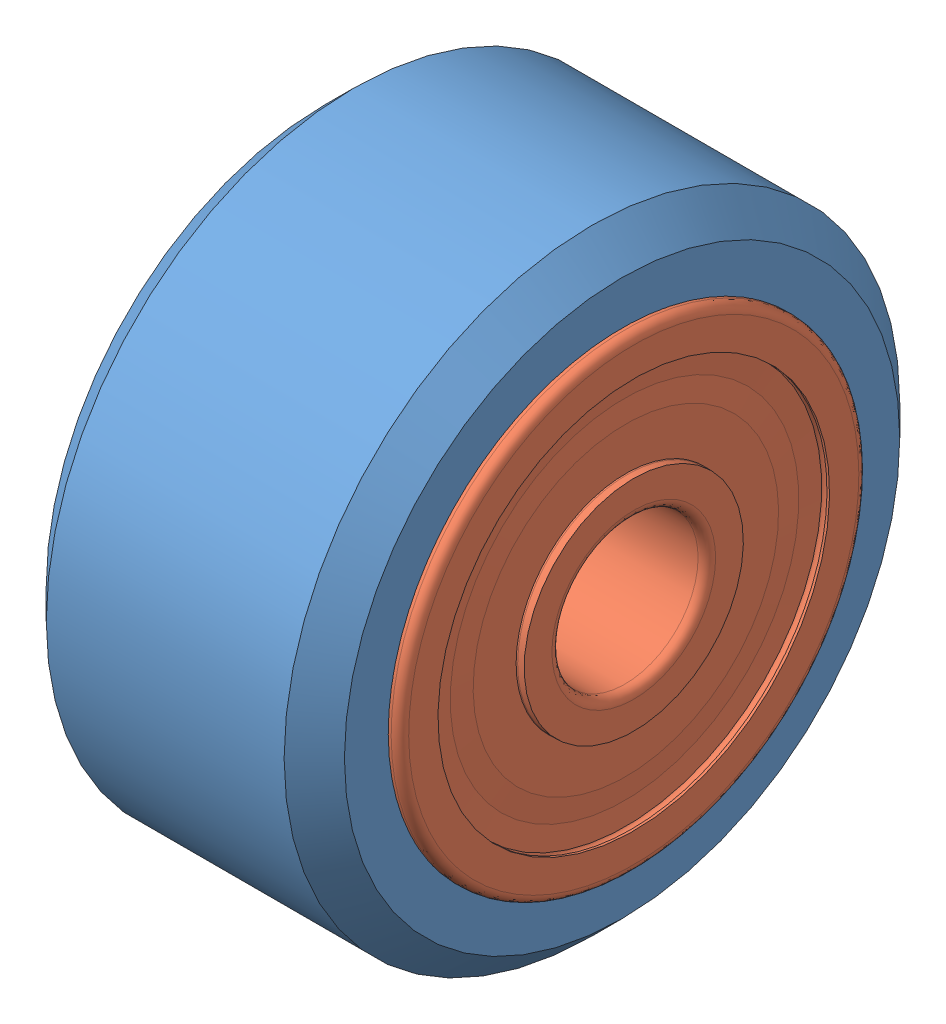
SolidWorks assembly v wheel, configuration Default. Lengths in mm.
Overall size (11 21.99 21.99).
3 component instances, 2 part files, 4 mates.
Components (placement in the parent):
- v wheel outer cover-1: v wheel outer cover [Default] at (5.3844 11.4744 17.147) size (6 21 21)
- W 625-2RS1-1: W 625-2RS1 [Default] at (5.8844 11.4744 17.147) x (1 0 0) z (0 0.854321 -0.519745) size (5 16 16)
- W 625-2RS1-2: W 625-2RS1 [Default] at (-0.1156 11.4744 17.147) size (5 16 16)
Mates (geometry in assembly coordinates):
- Concentric1: concentric aligned: cylinder of v wheel outer cover-1 through (5.3844 11.4744 17.147) axis (1 0 0) radius 10.5; cylinder of W 625-2RS1-1 through (55.8844 11.4744 17.147) axis (1 0 0) radius 8
- Coincident1: coincident aligned: plane of v wheel outer cover-1 through (5.8844 18.4744 17.147) normal (1 0 0); circle of W 625-2RS1-1
- Concentric2: concentric aligned: cylinder of v wheel outer cover-1 through (5.3844 11.4744 17.147) axis (1 0 0) radius 10.5; cylinder of W 625-2RS1-2 through (49.8844 11.4744 17.147) axis (1 0 0) radius 8
- Coincident2: coincident anti-aligned: plane of v wheel outer cover-1 through (4.8844 18.4744 17.147) normal (-1 0 0); plane of W 625-2RS1-2 through (4.8844 18.1744 17.147) normal (1 0 0)
